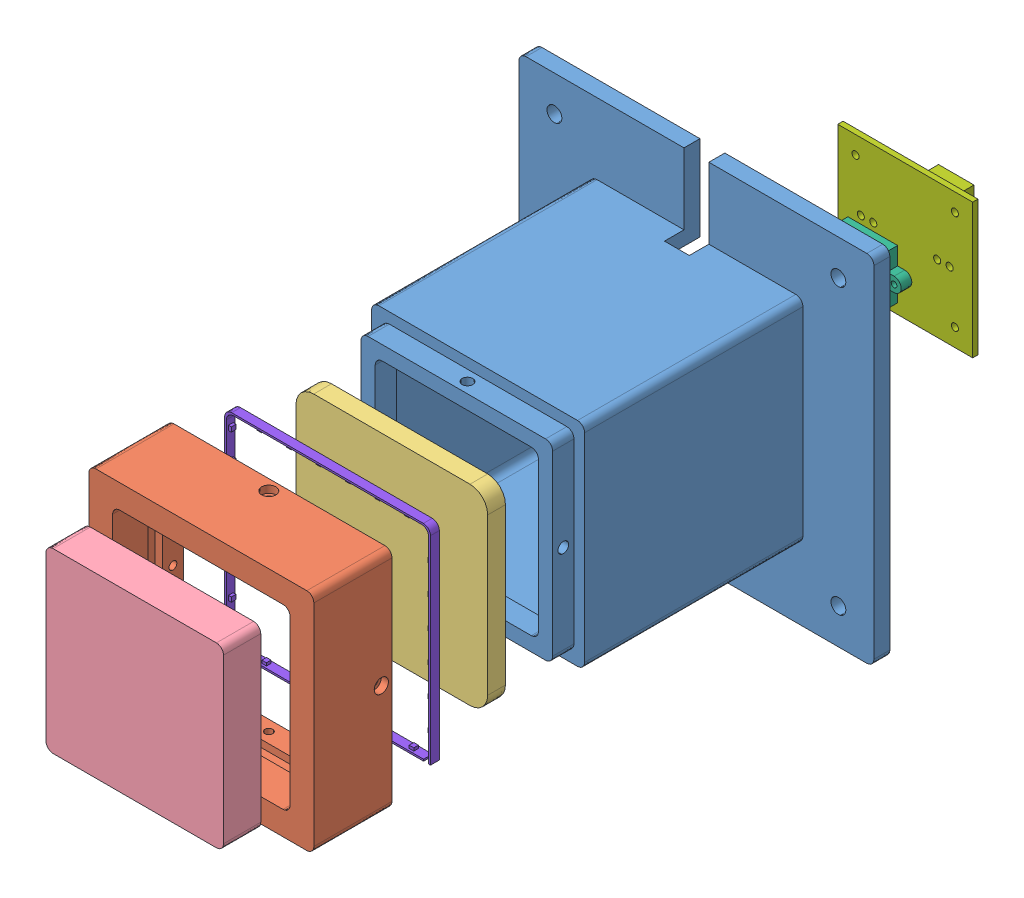
SolidWorks assembly 传感器大, configuration Default. Lengths in mm.
Overall size (100 100 227.05).
8 component instances, 8 part files, 19 mates.
Components (placement in the parent):
- 新版上加长20mm-1: 新版上加长20mm [默认] at (61.3572 -8.7985 87.6114) size (100 100 72)
- 新版下-3: 新版下 [默认] at (63.0572 -10.4985 197.7714) x (0 0 1) z (1 0 0) size (22 63.4 63.4)
- 亚克力均匀-1: 亚克力均匀 [默认] at (63.0572 -10.4985 166.1094) x (1 0 0) z (0 1 0) size (54 5 54)
- 透明弹性体-1: 透明弹性体 [默认] at (63.0572 -10.4985 228.0335) x (1 0 0) z (0 -1 0) size (50 10.5 50)
- 摄像头上-1: 摄像头上 [默认] at (61.5572 -8.9985 56.3678) x (1 0 0) z (0 -1 0) size (14 12 14)
- 镜头中-1: 镜头中 [默认] at (61.5572 -8.9985 29.1304) x (1 0 0) z (0 -1 0) size (22 11 14)
- 镜头下-1: 镜头下 [默认] at (61.5572 -8.9985 18.4883) x (0 0 1) z (-1 0 0) size (8.5 38 38)
- LED-3: LED [默认] at (63.0572 -10.4985 184.2301) x (1 0 0) z (0 1 0) size (58 2.5 58)
Mates (geometry in assembly coordinates):
- 平行2: parallel anti-aligned: plane of 新版上加长20mm-1 through (52.7228 -0.0515 146.1114) normal (0 0 1); plane of 新版下-3 through (54.4228 -1.7515 208.0025) normal (0 0 -1)
- 平行3: parallel aligned: plane of 新版上加长20mm-1 through (82.7228 29.9485 143.1114) normal (1 0 0); plane of 新版下-3 through (86.1228 -33.4515 230.0025) normal (1 0 0)
- 重合6: coincident aligned: plane of 新版上加长20mm-1 through (22.7228 29.9485 143.1114) normal (0 1 0); plane of 新版下-3 through (86.1228 29.9485 230.0025) normal (0 1 0)
- 重合5: coincident aligned: plane of 新版上加长20mm-1 through (22.7228 29.9485 143.1114) normal (-1 0 0); plane of 新版下-3 through (22.7228 -33.4515 230.0025) normal (-1 0 0)
- 平行5: parallel anti-aligned: plane of 新版上加长20mm-1 through (29.7228 22.9485 140.1114) normal (0 -1 0); plane of 亚克力均匀-1 through (27.4228 25.2485 184.151) normal (0 1 0)
- 平行6: parallel: line of 新版上加长20mm-1 through (73.7228 22.9485 146.1114) axis (-1 0 0); plane of 亚克力均匀-1 through (27.4228 25.2485 184.151) normal (0 1 0)
- 重合13: coincident anti-aligned: plane of 新版下-3 through (27.4228 -28.7515 220.0025) normal (1 0 0); plane of 亚克力均匀-1 through (27.4228 -28.7515 184.151) normal (-1 0 0)
- 重合14: coincident anti-aligned: plane of 新版下-3 through (27.4228 25.2485 220.0025) normal (0 -1 0); plane of 亚克力均匀-1 through (27.4228 25.2485 184.151) normal (0 1 0)
- 重合17: coincident anti-aligned: plane of 新版下-3 through (79.4228 -26.7515 220.0025) normal (-1 0 0); plane of 透明弹性体-1 through (79.4228 23.2485 256.7164) normal (1 0 0)
- 重合18: coincident anti-aligned: plane of 新版下-3 through (79.4228 -26.7515 220.0025) normal (0 1 0); plane of 透明弹性体-1 through (29.4228 -26.7515 256.7164) normal (0 -1 0)
- 重合23: coincident anti-aligned: plane of 新版上加长20mm-1 through (71.9228 19.1485 91.6114) normal (-1 0 0); plane of 镜头下-1 through (71.9228 18.7485 21.2203) normal (1 0 0)
- 重合25: coincident anti-aligned: plane of 新版上加长20mm-1 through (71.9228 -19.2515 91.6114) normal (0 1 0); plane of 镜头下-1 through (33.9228 -19.2515 21.2203) normal (0 -1 0)
- 平行8: parallel anti-aligned: plane of 镜头中-1 through (52.9228 -0.2515 30.1132) normal (0 0 -1); plane of 镜头下-1 through (52.9228 -0.2515 21.2203) normal (0 0 1)
- 同心6: concentric aligned: cylinder of 镜头中-1 through (43.9228 -0.2515 30.1132) axis (0 0 1) radius 0.8; cylinder of 镜头下-1 through (43.9228 -0.2515 11.2203) axis (0 0 1) radius 1
- 平行11: parallel anti-aligned: plane of 摄像头上-1 through (52.9228 -0.2515 45.3483) normal (0 0 -1); plane of 镜头中-1 through (52.9228 -0.2515 34.1132) normal (0 0 1)
- 同心10: concentric aligned: cylinder of 摄像头上-1 through (52.9228 -0.2515 45.3483) axis (0 0 1) radius 6; cylinder of 镜头中-1 through (52.9228 -0.2515 34.1132) axis (0 0 1) radius 6.4
- 同心11: concentric aligned: cylinder of 镜头中-1 through (61.9228 -0.2515 30.1132) axis (0 0 1) radius 0.8; cylinder of 镜头下-1 through (61.9228 -0.2515 11.2203) axis (0 0 1) radius 1
- 重合34: coincident anti-aligned: plane of 新版下-3 through (83.4228 -1.7515 208.0025) normal (-1 0 0); plane of LED-3 through (83.4228 -30.7515 214.1275) normal (1 0 0)
- 重合35: coincident anti-aligned: plane of 新版下-3 through (54.4228 -30.7515 208.0025) normal (0 1 0); plane of LED-3 through (25.4228 -30.7515 214.1275) normal (0 -1 0)
